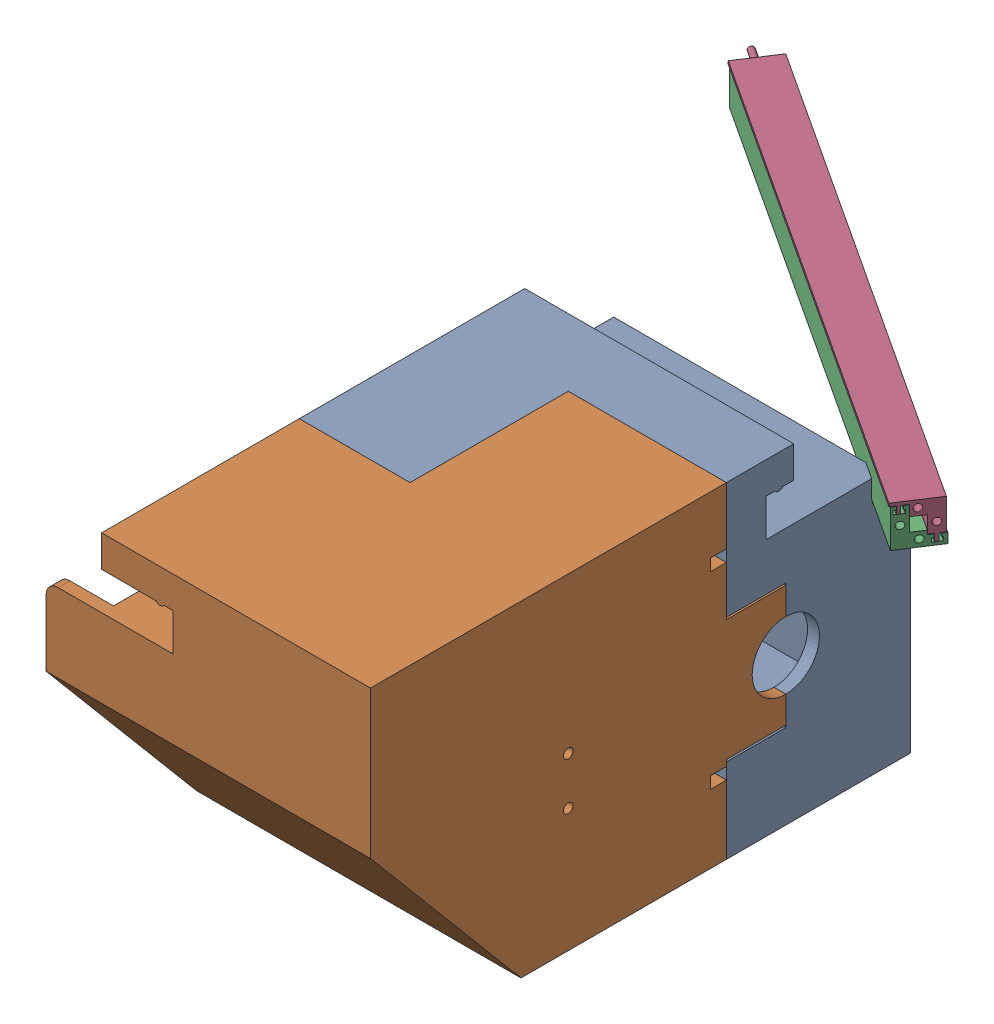
SolidWorks assembly Assem1COVERandMotorSupport, configuration Default. Lengths in mm.
Overall size (127.36 82.5 205.96).
4 component instances, 4 part files, 3 mates.
Components (placement in the parent):
- motorSupportWORMGEAR-1: motorSupportWORMGEAR [Default] at (-79.2126 51.9708 25.0548) size (82 82.5 86.5)
- wormGearSupportCOVER-1: wormGearSupportCOVER [Default] at origin size (82 82.5 105)
- wireConcealingFEMALE-1: wireConcealingFEMALE [Default] at (-71.0368 -46.9105 -57.6971) x (0.837169 0 0.546944) z (-0.546944 0 0.837169) size (145 10.5 10.5)
- Backup of wireConcealingMALE-1: Backup of wireConcealingMALE [Default] at (-91.7155 117.1701 -26.0456) x (0.837169 0 0.546944) z (0.546944 0 -0.837169) size (145 10.5 10.67)
Mates (geometry in assembly coordinates):
- Coincident1: coincident anti-aligned: plane of wireConcealingFEMALE-1 through (-2.5114 30.6798 -12.9277) normal (0 1 0); plane of Backup of wireConcealingMALE-1 through (-23.1901 30.6798 18.7238) normal (0 -1 0)
- Coincident2: coincident anti-aligned: plane of wireConcealingFEMALE-1 through (-24.9465 36.1798 -7.8414) normal (0.837169 0 0.546944); plane of Backup of wireConcealingMALE-1 through (-36.5848 30.6798 9.9727) normal (-0.837169 0 -0.546944)
- Coincident3: coincident anti-aligned: plane of wireConcealingFEMALE-1 through (-11.2236 -46.9105 0.4075) normal (0.546944 0 -0.837169); plane of Backup of wireConcealingMALE-1 through (-11.2236 117.1701 0.4075) normal (-0.546944 0 0.837169)
